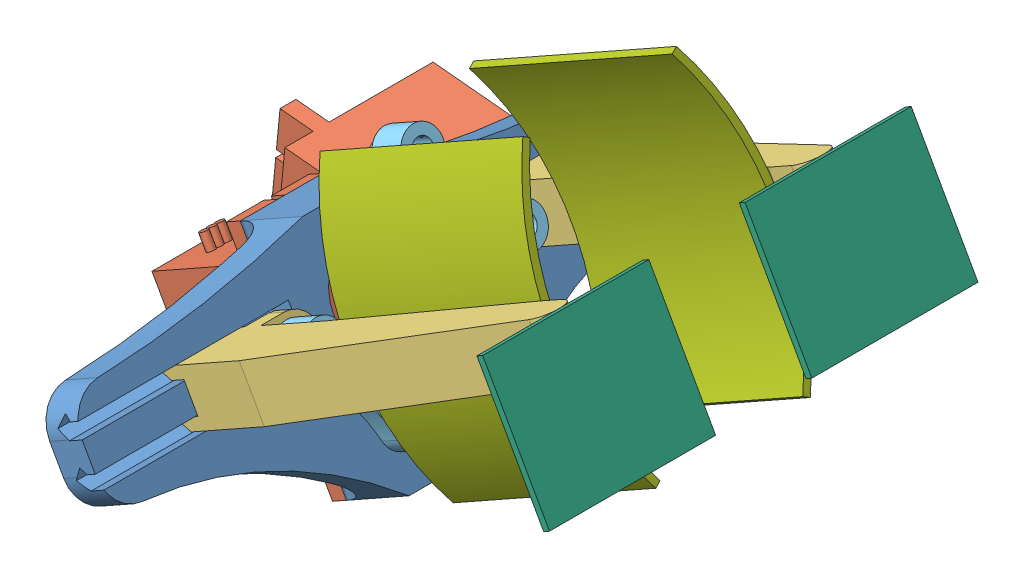
SolidWorks assembly Linear Gripper, configuration Default. Lengths in mm.
Overall size (97.64 78.78 87.8).
13 component instances, 8 part files, 30 mates.
Components (placement in the parent):
- Linear Base-1: Linear Base [Default] x (0.871723 0.489999 0) z (0 0 1) size (35.83 33.39 87.8)
- Servo Micro-2: Servo Micro [Default] at (-4.4917 -2.5194 15.2) x (0.489999 -0.871723 0) z (0 0 1) size (32.6 29.9 12.4)
- LGrip-1: LGrip [Default] at (19.0994 14.389 38.7179) x (0 0 -1) z (0.871723 0.489999 0) size (17.35 8.47 59.1)
- Horn-1: Horn [По умолчанию] at (20.5558 17.4104 15.2) x (-0.444655 0.791055 -0.420135) z (-0.871723 -0.489999 0) size (32 7.5 5)
- Linear Link-1: Linear Link [Default] at (26.3947 13.1452 25.7549) x (0.405503 -0.721403 -0.561378) z (-0.275075 0.489366 -0.827559) size (21.9 5 6)
- Linear Link-2: Linear Link [Default] at (19.9104 24.6809 4.5365) x (0.400881 -0.713179 -0.57504) z (-0.281769 0.501275 -0.818125) size (21.9 5 6)
- Servo Micro-3: Servo Micro [Default] at (-5.0766 0.4882 -26.6) x (-0.995407 0.095729 0) z (0.095729 0.995407 0) size (32.6 29.9 12.4)
- kicking-1: kicking [Default] at (70.7212 38.2668 27.3654) x (0 0 1) z (-0.871723 -0.489999 0) size (25 20.5 1)
- kicking-2: kicking [Default] at (70.6477 38.3976 -12.1826) x (0 0 1) z (-0.871723 -0.489999 0) size (25 20.5 1)
- Part1^Linear Gripper-1: Part1^Linear Gripper [Default] at origin (virtual)
- grabber-2: grabber [Default] at (40.3843 5.6001 25.8815) x (-0.000847 0.001507 0.999999) z (-0.489998 0.871722 -0.001729) size (6.52 35 41)
- grabber-3: grabber [Default] at (20.7109 40.5998 4.3705) x (-0.000847 0.001507 -0.999999) z (0.489998 -0.871722 -0.001729) size (6.52 35 41)
- LGrip-2: LGrip [Default] at (17.1441 17.8676 -8.5351) x (0 0 1) z (0.871723 0.489999 0) size (17.35 8.47 59.1)
Mates (geometry in assembly coordinates):
- Parallel1: parallel aligned: plane of Linear Base-1 through (3.7619 2.1146 7) normal (0 0 1); plane of Servo Micro-2 through (9.4107 18.2581 21.4) normal (0 0 1)
- Coincident8: coincident anti-aligned: plane of Linear Base-1 through (3.2559 20.5342 21.4) normal (-0.871723 -0.489999 0); plane of Servo Micro-2 through (3.2559 20.5342 21.4) normal (0.871723 0.489999 0)
- Concentric2: concentric anti-aligned: circle of Servo Micro-2; circle of Horn-1
- Coincident11: coincident: plane of Servo Micro-2 through (18.6961 10.5146 15.2) normal (0.871723 0.489999 0); plane of Horn-1 through (16.1971 14.9604 15.2) normal (-0.871723 -0.489999 0)
- Concentric3: concentric aligned: circle of Linear Base-1; circle of Servo Micro-2
- Coincident12: coincident anti-aligned: plane of Linear Base-1 through (20.6598 11.613 -23) normal (0.871723 0.489999 0); plane of LGrip-1 through (19.0994 14.389 38.7179) normal (-0.871723 -0.489999 0)
- Distance3: distance = 0.15 mm anti-aligned: plane of Linear Base-1 through (-4.4613 7.9368 27.1) normal (0.489999 -0.871723 0); plane of LGrip-1 through (16.1413 19.3455 29.5159) normal (-0.489999 0.871723 0)
- Concentric4: concentric anti-aligned: circle of LGrap-1; circle of Linear Link-1
- Concentric5: concentric aligned: circle of Horn-1; circle of Linear Link-1
- Coincident17: coincident anti-aligned: plane of Horn-1 through (20.5558 17.4104 15.2) normal (0.871723 0.489999 0); plane of Linear Link-1 through (20.5558 17.4104 30.2179) normal (-0.871723 -0.489999 0)
- LimitDistance1: limit distance = 6.6179 mm anti-aligned: plane of LGrip-1 through (26.309 11.7671 33.7179) normal (0 0 -1); plane of Linear Base-1 through (0 0 27.1) normal (0 0 1)
- Concentric6: concentric anti-aligned: circle of Horn-1; circle of Linear Link-2
- Coincident20: coincident anti-aligned: plane of Horn-1 through (20.5558 17.4104 15.2) normal (0.871723 0.489999 0); plane of Linear Link-2 through (14.1083 28.8807 9.108) normal (-0.871723 -0.489999 0)
- Concentric8: concentric aligned: cylinder of Linear Base-1 through (0 0 7) axis (0 0 -1) radius 2; cylinder of Servo Micro-3 through (0 0 3.3) axis (0 0 -1) radius 2.5
- Coincident22: coincident anti-aligned: plane of Linear Base-1 through (3.7619 2.1146 0) normal (0 0 -1); plane of Servo Micro-3 through (-5.0766 0.4882 0) normal (0 0 1)
- Coincident23: coincident anti-aligned: plane of LGrip-1 through (94.0581 -5.2911 37.3654) normal (0.871723 0.489999 0); plane of kicking-1 through (69.8495 37.7768 27.3654) normal (-0.871723 -0.489999 0)
- Coincident24: coincident aligned: plane of LGrip-1 through (16.1413 19.3455 29.5159) normal (-0.489999 0.871723 0); plane of kicking-1 through (64.827 46.712 22.3654) normal (-0.489999 0.871723 0)
- Coincident25: coincident: point of LGrip-1; unknown of kicking-1
- Coincident31: coincident: unknown of LGrip-1; unknown of grabber-2
- Parallel4: parallel anti-aligned: plane of kicking-1 through (69.8495 37.7768 27.3654) normal (-0.871723 -0.489999 0); plane of grabber-2 through (61.124 40.1323 -8.7941) normal (0.871723 0.489999 0)
- Parallel5: parallel anti-aligned: plane of kicking-2 through (69.776 37.9076 -12.1826) normal (-0.871723 -0.489999 0); plane of grabber-3 through (61.0505 40.2631 38.9768) normal (0.871723 0.489999 0)
- Distance5: distance = 18.7356 mm: point of grabber-2; point of kicking-1
- Coincident35: coincident anti-aligned: plane of Linear Base-1 through (20.6598 11.613 -23) normal (0.871723 0.489999 0); plane of LGrip-2 through (17.1441 17.8676 -8.5351) normal (-0.871723 -0.489999 0)
- Coincident36: coincident anti-aligned: plane of Linear Base-1 through (-4.4613 7.9368 3.3) normal (0.489999 -0.871723 0); plane of LGrip-2 through (16.0678 19.4763 0.6669) normal (-0.489999 0.871723 0)
- Concentric10: concentric anti-aligned: cylinder of Linear Link-2 through (20.4823 17.5411 -0.0351) axis (0.871723 0.489999 0) radius 1.5; cylinder of LGrip-2 through (29.7616 22.7571 -0.0351) axis (-0.871723 -0.489999 0) radius 0.75
- Coincident37: coincident anti-aligned: plane of kicking-2 through (69.776 37.9076 -12.1826) normal (-0.871723 -0.489999 0); plane of LGrip-2 through (39.2954 92.1335 -7.1826) normal (0.871723 0.489999 0)
- Coincident38: coincident aligned: plane of kicking-2 through (64.7535 46.8427 -17.1826) normal (-0.489999 0.871723 0); plane of LGrip-2 through (16.0678 19.4763 0.6669) normal (-0.489999 0.871723 0)
- Coincident39: coincident: unknown of kicking-2; unknown of LGrip-2
- Coincident42: coincident: point of grabber-3; point of LGrip-2
- Distance8: distance = 18.7356 mm: point of grabber-3; point of kicking-2
